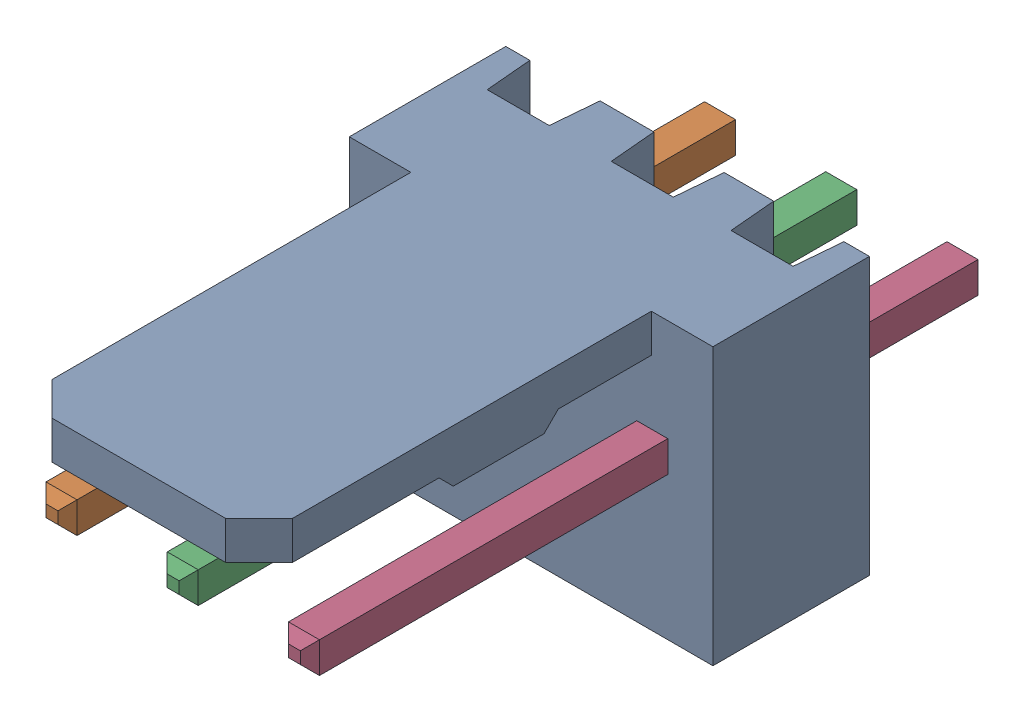
SolidWorks assembly Molex PCB 3 pin v2 v6_3, configuration Predeterminado. Lengths in mm.
Overall size (7.62 5.79 14.92).
4 component instances, 2 part files, 0 mates.
Components (placement in the parent):
- BASE9710016_2-1: BASE9710016_2 [Predeterminado] at (2.54 2.895 -8.22) size (7.62 5.79 11.5)
- PINO9710016_2-1: PINO9710016_2 [Predeterminado] at (1.27 3.325 -0.72) size (0.65 0.65 14.2)
- PINO9710016_2-2: PINO9710016_2 [Predeterminado] at (3.81 3.325 -0.72) size (0.65 0.65 14.2)
- PINO9710016_2-3: PINO9710016_2 [Predeterminado] at (6.35 3.325 -0.72) size (0.65 0.65 14.2)
